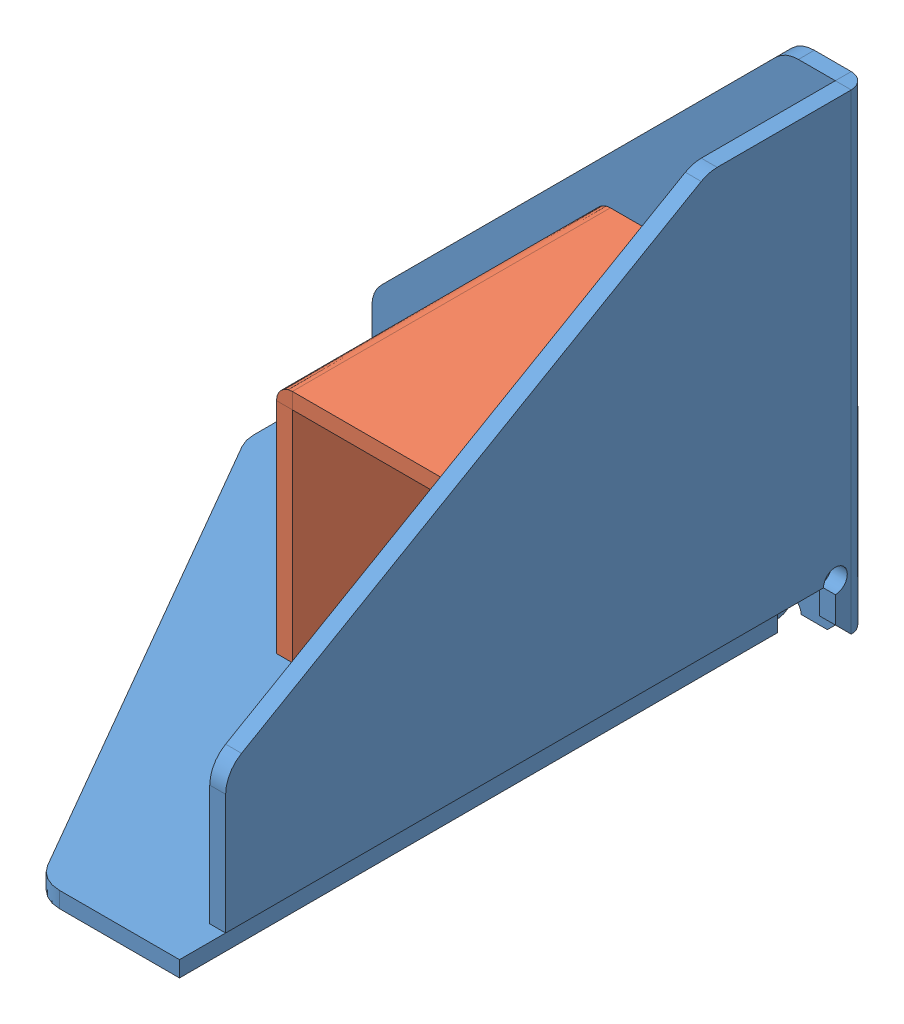
SolidWorks assembly 連接補強座-1, configuration 預設. Lengths in mm.
Overall size (120.61 124.61 161.4).
2 component instances, 2 part files, 3 mates.
Components (placement in the parent):
- LB-A54A-02-32-1: LB-A54A-02-32 [預設] at (-84294.0927 8119.5382 -80.691) size (120.61 124.61 161.4)
- LB-A54-02-5-1: LB-A54-02-5 [預設] at (-51.817 10.2837 -76.691) x (0 1 0) z (1 0 0) size (64.1 80 64.1)
Mates (geometry in assembly coordinates):
- 重合/共線/共點1: coincident: plane of LB-A54A-02-32-1 through (-2.817 9.7837 -76.691) normal (0 0 1); plane of LB-A54-02-5-1 through (7.283 70.3837 -76.691) normal (0 0 -1)
- 重合/共線/共點2: coincident: line of LB-A54A-02-32-1 through (-49.817 74.3837 -80.691) axis (1 0 0); plane of LB-A54-02-5-1 through (-108.917 74.3837 3.309) normal (0 1 0)
- 重合/共線/共點3: coincident: line of LB-A54A-02-32-1 through (-51.817 -70.2163 -80.691) axis (0 1 0); plane of LB-A54-02-5-1 through (-51.817 10.2837 3.309) normal (-1 0 0)
